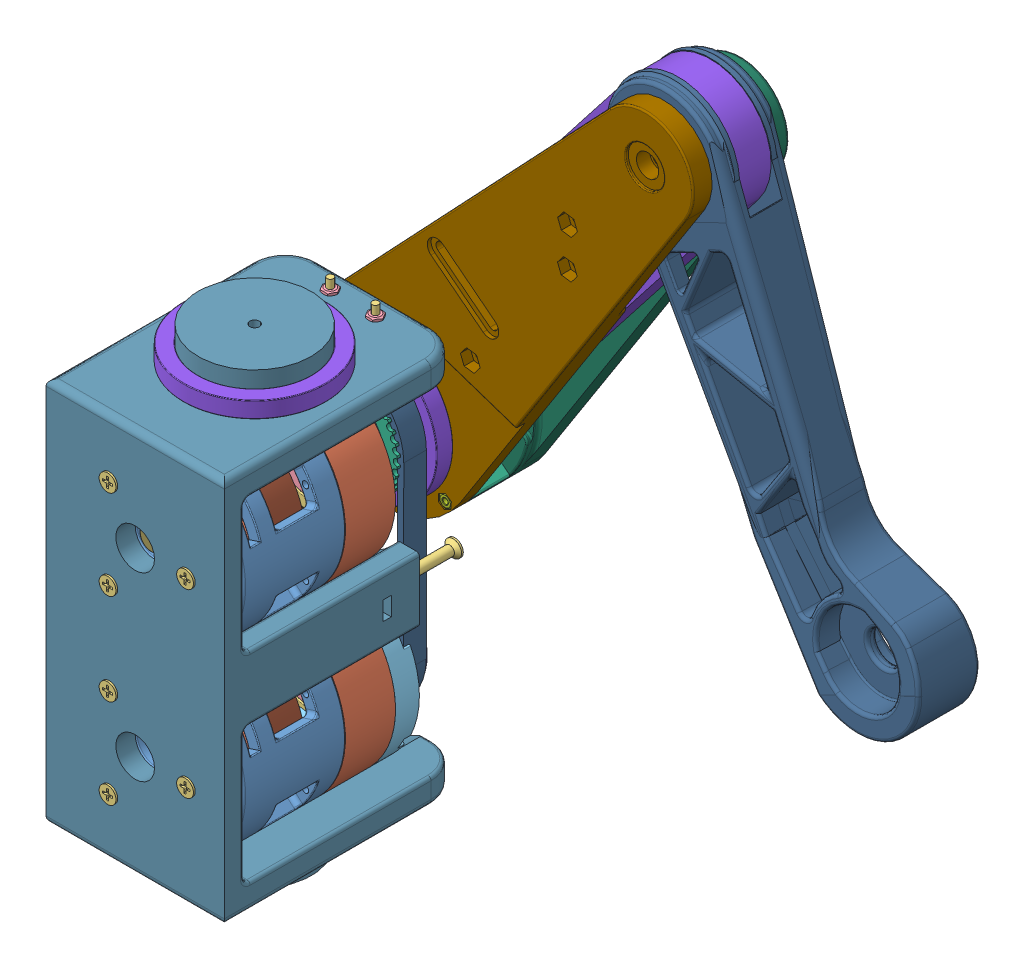
SolidWorks assembly 关节5_0版本, configuration 默认. Lengths in mm.
Overall size (206.88 234.04 105.8).
72 component instances, 34 part files, 145 mates.
Components (placement in the parent):
- 电机座-1: 电机座 [默认] at (-8.5436 5.9652 39.45) size (55.2 55.2 31.5)
- 减速器壳体-1: 减速器壳体 [默认] at (-8.5436 5.9652 32.95) x (-0.630606 -0.776103 0) z (0 0 -1) size (55.2 55.2 15.5)
- 减速器上盖-1: 减速器上盖 [默认] at (-8.5436 5.9652 18.45) x (0.969233 -0.246145 0) z (0 0 1) size (55.2 55.2 7.4) (hidden)
- 30-37-4轴承6-1: 30-37-4轴承6 [默认] at (-8.5436 5.9652 17.95) x (0.205581 0.97864 0) z (0 0 1) size (37 37 4)
- 输出轴-1: 输出轴 [默认] at (-8.5436 5.9652 21.55) x (0.166349 0.986067 0) z (0 0 -1) size (35 35 10)
- 电机座-2: 电机座 [默认] at (-8.5436 -50.0348 39.45) size (55.2 55.2 31.5)
- 减速器壳体-2: 减速器壳体 [默认] at (-8.5436 -50.0348 32.95) x (-0.630606 -0.776103 0) z (0 0 -1) size (55.2 55.2 15.5)
- 减速器上盖-2: 减速器上盖 [默认] at (-8.5436 -50.0348 18.45) x (1 0.000767 0) z (0 0 1) size (55.2 55.2 7.4)
- 输出轴-2: 输出轴 [默认] at (-8.5436 -50.0348 21.55) x (-0.988058 0.154081 0) z (0 0 -1) size (35 35 10)
- 30-37-4轴承6-2: 30-37-4轴承6 [默认] at (-8.5436 -50.0348 17.95) size (37 37 4)
- 光杆同步轮10-1: 光杆同步轮10 [GearTrax] at (-8.5436 5.9652 10.55) x (0.788067 -0.615589 0) z (0 0 1) size (35.45 35.52 14.5)
- 17-23-4轴承-1: 17-23-4轴承 [默认] at (-8.5436 5.9652 8.55) x (-0.69858 -0.715532 0) z (0 0 1) size (23 23 4)
- 35-44-5轴承-1: 35-44-5轴承 [默认] at (-8.5436 5.9652 5.55) x (-0.386204 0.922413 0) z (0 0 -1) size (44 44 5)
- 大足-1: 大足 [默认] at (-8.5436 5.9652 -2.7) x (-0.788067 0.615589 0) z (0 0 1) size (55.2 177.6 19.75)
- 零件2-1: 零件2 [默认] at origin
- 小足-1: 小足 [GearTrax] at (74.5609 112.3542 -13.1) x (0.917786 0.397075 0) z (0 0 1) size (50.75 159.33 20.11)
- 零件5-1: 零件5 [默认] at (-8.5436 5.9652 8.55) x (0 -1 0) z (0 0 1)
- 保持架-1: 保持架 [默认] at (-8.5436 5.9652 0.55) x (0 -1 0) z (-1 0 0) size (112 17 56) (hidden)
- 光杆同步轮-1: 光杆同步轮 [GearTrax] at (-8.5436 5.9652 -12.25) x (0.986067 -0.166349 0) z (0 0 1) size (35.45 35.52 10)
- 传动轴-1: 传动轴 [默认] at (-8.5436 5.9652 16.55) x (-0.986067 0.166349 0) z (0 0 -1) size (20 20 39)
- 键-1: 键 [默认] at (-7.1297 14.3467 -6.9375) x (0.986067 -0.166349 0) z (0.166349 0.986067 0) size (4.2 10.5 4.5)
- 17-23-4轴承-2: 17-23-4轴承 [默认] at (-8.5436 5.9652 -18.45) x (0.398989 0.916956 0) z (0 0 -1) size (23 23 4)
- 支撑架-1: 支撑架 [默认] at (-8.5436 -22.0348 70.95) x (0 -1 0) z (-1 0 0) size (139.2 74 55.2)
- 17-23-4轴承-3: 17-23-4轴承 [默认] at (-8.5436 5.9652 -5.45) x (0.931595 -0.363497 0) z (0 0 1) size (23 23 4)
- 大足2-1: 大足2 [默认] at (-8.5436 5.9652 -17.45) x (0.788067 -0.615589 0) z (0 0 -1) size (55.62 177.6 10.15)
- 同步轮-1: 同步轮 [GearTrax] at (74.5609 112.3542 -13.1) size (35.45 35.52 10)
- 111-1: 111 [GearTrax] at (-8.5436 -50.0348 5.3204) x (-1 0.000603 0) z (0 0 -1) size (36 36 12)
- 张紧轮-1: 张紧轮 [默认] at (-20.9196 -21.7585 13.55) x (0.998843 -0.048088 0) z (0.048088 0.998843 0) size (4.1 6.5 4.1)
- 端盖-1: 端盖 [默认] at (-8.5436 5.9652 -22.95) x (0.94954 -0.313647 0) z (0.313647 0.94954 0) size (22 3 22)
- cross countersunk head screw_as-2: cross countersunk head screw_as [AS-NZS 1023 CC- M2 x 12-N] at (-16.5463 -4.2797 -5.8) x (0 0 1) z (0.001298 -0.999999 0) size (12 3.8 3.8)
- cross countersunk head screw_as-3: cross countersunk head screw_as [AS-NZS 1023 CC- M2 x 16-N] at (-18.7885 13.9678 -6) x (0 0 1) z (-0.923728 -0.383049 0) size (16 3.8 3.8)
- cross countersunk head screw_as-4: cross countersunk head screw_as [AS-NZS 1023 CC- M2 x 16-N] at (-0.541 16.21 -6) x (0 0 1) z (-0.923728 -0.383049 0) size (16 3.8 3.8)
- cross recessed countersunk head screws gb1-2: cross recessed countersunk head screws gb1 [GB_CROSS_SCREWS_TYPE4 M2X14-12.8  H type-N] at (-1.5436 -71.0848 9.55) x (0 -1 0) z (-0.757131 0 0.653264) size (14 3.5 3.5)
- cross recessed countersunk head screws gb1-4: cross recessed countersunk head screws gb1 [GB_CROSS_SCREWS_TYPE4 M2X14-12.8  H type-N] at (-15.5436 27.5152 9.55) x (0 1 0) z (-0.215611 0 0.976479) size (14 3.5 3.5)
- cross recessed countersunk head screws gb1-5: cross recessed countersunk head screws gb1 [GB_CROSS_SCREWS_TYPE4 M2X14-12.8  H type-N] at (-15.5436 -71.0848 9.55) x (0 -1 0) z (-0.946389 0 -0.32303) size (14 3.5 3.5)
- cross recessed countersunk head screws gb1-6: cross recessed countersunk head screws gb1 [GB_CROSS_SCREWS_TYPE4 M3X30-28.35  H type-N] at (13.0564 -21.7585 -0.45) x (0 0 1) z (-1 0 0) size (30 5.2 5.2)
- cross recessed countersunk head screws gb1-7: cross recessed countersunk head screws gb1 [GB_CROSS_SCREWS_TYPE4 M3X30-28.35  H type-N] at (-30.1436 -21.7585 -0.45) x (0 0 1) z (0 1 0) size (30 5.2 5.2) (hidden)
- cross recessed countersunk head screws gb1-8: cross recessed countersunk head screws gb1 [GB_CROSS_SCREWS_TYPE4 M2X10-8.8  H type-N] at (0.1136 -55.0401 7.1) x (0 0 1) z (-0.066077 0.997815 0) size (10 3.5 3.5)
- cross recessed countersunk head screws gb1-9: cross recessed countersunk head screws gb1 [GB_CROSS_SCREWS_TYPE4 M2X10-8.8  H type-N] at (-8.5376 -40.0348 7.1) x (0 0 1) z (0.070804 -0.99749 0) size (10 3.5 3.5)
- cross recessed countersunk head screws gb1-10: cross recessed countersunk head screws gb1 [GB_CROSS_SCREWS_TYPE4 M2X10-8.8  H type-N] at (-17.2069 -55.0296 7.1) x (0 0 1) z (0.420444 -0.907319 0) size (10 3.5 3.5)
- hex thin nuts-grades ab-chamfered gb-1: hex thin nuts-grades ab-chamfered gb [GB_FASTENER_NUT_STNAB M2-N] at (-15.5436 38.7652 9.55) x (1 0 0) z (0 1 0) size (4.62 4 1.2)
- hex thin nuts-grades ab-chamfered gb-2: hex thin nuts-grades ab-chamfered gb [GB_FASTENER_NUT_STNAB M2-N] at (-1.5436 38.7652 9.55) x (1 0 0) z (0 1 0) size (4.62 4 1.2)
- hex thin nuts-grades ab-chamfered gb-3: hex thin nuts-grades ab-chamfered gb [GB_FASTENER_NUT_STNAB M2-N] at (-15.5436 -82.8348 9.55) x (0.837169 0 0.546944) z (0 -1 0) size (4.62 4 1.2)
- hex thin nuts-grades ab-chamfered gb-4: hex thin nuts-grades ab-chamfered gb [GB_FASTENER_NUT_STNAB M2-N] at (-1.5436 -82.8348 9.55) x (0.837169 0 0.546944) z (0 -1 0) size (4.62 4 1.2)
- 定位环-1: 定位环 [默认] at (-8.5436 5.9652 -7.25) x (0.991883 0.127157 0) z (0.127157 -0.991883 0) size (20.4 1.65 20.4)
- cross recessed countersunk head screws gb1-11: cross recessed countersunk head screws gb1 [GB_CROSS_SCREWS_TYPE4 M3X14-12.35  H type-N] at (-16.5436 19.8216 77.5) x (0 0 -1) z (1 0 0) size (14 5.2 5.2)
- cross recessed countersunk head screws gb1-12: cross recessed countersunk head screws gb1 [GB_CROSS_SCREWS_TYPE4 M3X14-12.35  H type-N] at (-16.5436 -7.8913 77.5) x (0 0 -1) z (1 0 0) size (14 5.2 5.2)
- cross recessed countersunk head screws gb1-13: cross recessed countersunk head screws gb1 [GB_CROSS_SCREWS_TYPE4 M3X14-12.35  H type-N] at (7.4564 5.9652 77.5) x (0 0 -1) z (1 0 0) size (14 5.2 5.2)
- cross recessed countersunk head screws gb1-14: cross recessed countersunk head screws gb1 [GB_CROSS_SCREWS_TYPE4 M3X14-12.35  H type-N] at (-16.5436 -36.1784 77.5) x (0 0 -1) z (1 0 0) size (14 5.2 5.2)
- cross recessed countersunk head screws gb1-15: cross recessed countersunk head screws gb1 [GB_CROSS_SCREWS_TYPE4 M3X14-12.35  H type-N] at (7.4564 -50.0348 77.5) x (0 0 -1) z (1 0 0) size (14 5.2 5.2)
- cross recessed countersunk head screws gb1-16: cross recessed countersunk head screws gb1 [GB_CROSS_SCREWS_TYPE4 M3X14-12.35  H type-N] at (-16.5436 -63.8913 77.5) x (0 0 -1) z (1 0 0) size (14 5.2 5.2)
- 支撑半环-1: 支撑半环 [默认] at (-8.5436 5.9652 -17.45) x (-0.788117 0.615526 0) z (0.615526 0.788117 0) size (55.19 11.85 27.6)
- hex nuts, style 1-grades ab gb-1: hex nuts, style 1-grades ab gb [GB_FASTENER_NUT_SNAB1 M3-N] at (13.0564 -21.7585 27.65) x (0.971016 0.239013 0) z (0 0 1) size (6.35 5.5 2.4)
- hex nuts, style 1-grades ab gb-2: hex nuts, style 1-grades ab gb [GB_FASTENER_NUT_SNAB1 M3-N] at (-30.1436 -21.7585 27.65) size (6.35 5.5 2.4)
- 零件2^关节5_0版本-1: 零件2^关节5_0版本 [默认] at origin (virtual)
- 同步带-1: 同步带 [默认] at (-8.5436 5.9652 -18.1) x (0.615589 0.788067 0) z (0.788067 -0.615589 0) size (172.52 10 37.52)
- 定位环_17_20_1-2mm-1: 定位环_17_20_1-2mm [默认] at (-8.5436 5.9652 -18.45) x (1 0 0) z (0 -1 0) size (20 1.2 20)
- 同步带168-2: 同步带168 [默认] at (-8.5436 5.9652 5.55) x (-0.000603 -1 0) z (-1 0.000603 0) size (93.52 7 37.52)
- cross recessed countersunk head screws gb1-17: cross recessed countersunk head screws gb1 [GB_CROSS_SCREWS_TYPE4 M2X14-12.8  H type-N] at (-1.5436 27.5152 9.55) x (0 1 0) z (-0.215611 0 0.976479) size (14 3.5 3.5)
- cross recessed countersunk head screws gb1-18: cross recessed countersunk head screws gb1 [GB_CROSS_SCREWS_TYPE4 M2X16-14.8  H type-N] at (-20.9196 -21.7585 2.1) x (0 0 1) z (0.635217 0.772334 0) size (16 3.5 3.5)
- hex nuts, style 1-grades ab gb-3: hex nuts, style 1-grades ab gb [GB_FASTENER_NUT_SNAB1 M2-N] at (-20.9196 -21.7585 16.55) size (4.62 4 1.6)
- hex nuts, style 1-grades ab gb-4: hex nuts, style 1-grades ab gb [GB_FASTENER_NUT_SNAB1 M2-N] at (9.9207 -11.0371 -0.55) x (0.905621 0.424088 0) z (0 0 1) size (4.62 4 1.6)
- hex nuts, style 1-grades ab gb-5: hex nuts, style 1-grades ab gb [GB_FASTENER_NUT_SNAB1 M2-N] at (-29.5103 19.764 -0.55) x (0.89625 0.443549 0) z (0 0 1) size (4.62 4 1.6)
- hex nuts, style 1-grades ab gb-6: hex nuts, style 1-grades ab gb [GB_FASTENER_NUT_SNAB1 M2-N] at (-6.9684 -5.3378 -0.55) x (0.83225 -0.554401 0) z (0 0 1) size (4.62 4 1.6)
- cross recessed countersunk head screws gb1-20: cross recessed countersunk head screws gb1 [GB_CROSS_SCREWS_TYPE4 M2X20-18.8  H type-N] at (-23.9933 -13.8166 -28.3) x (0 0 1) z (-1 0 0) size (20 3.5 3.5) (hidden)
- cross recessed countersunk head screws gb1-21: cross recessed countersunk head screws gb1 [GB_CROSS_SCREWS_TYPE4 M2X20-18.8  H type-N] at (9.9235 -11.0341 -28.3) x (0 0 1) z (-1 0 0) size (20 3.5 3.5)
- cross recessed countersunk head screws gb1-22: cross recessed countersunk head screws gb1 [GB_CROSS_SCREWS_TYPE4 M2X20-18.8  H type-N] at (-29.5103 19.764 -28.3) x (0 0 1) z (-1 0 0) size (20 3.5 3.5) (hidden)
- cross countersunk head screw_as-5: cross countersunk head screw_as [AS-NZS 1023 CC- M2 x 12-N] at (-8.5436 5.9652 -25.7809) x (0 0 1) z (-0.983275 0.182124 0) size (12 3.8 3.8)
- 电机46-1: 电机46 [默认] at (-8.5436 5.9652 59.65) x (0.5 0.866025 0) z (-0.866025 0.5 0) size (46 26.5 46)
- 电机46-2: 电机46 [默认] at (-8.5436 -50.0348 59.65) x (0.5 0.866025 0) z (-0.866025 0.5 0) size (46 26.5 46)
- 磁铁-1: 磁铁 [默认] at (-8.5436 5.9652 68.95) x (0.972678 0.232157 0) z (0 0 1) size (7.2 7.2 3)
- 35-44-5轴承-2: 35-44-5轴承 [默认] at (-8.5436 42.5652 39.95) x (-0.622762 0 0.782412) z (0 -1 0) size (44 44 5)
Mates (geometry in assembly coordinates):
- 同心1: concentric anti-aligned: cylinder of 电机座-1 through (-8.5436 5.9652 67.45) axis (0 0 -1) radius 27.6; cylinder of 减速器壳体-1 through (-8.5436 5.9652 23.95) axis (0 0 1) radius 27.6
- 重合1: coincident anti-aligned: plane of 电机座-1 through (-8.5436 5.9652 39.45) normal (0 0 -1); plane of 减速器壳体-1 through (-8.5436 5.9652 39.45) normal (0 0 1)
- 同心2: concentric anti-aligned: cylinder of 减速器壳体-1 through (-8.5436 5.9652 23.95) axis (0 0 1) radius 27.6; cylinder of 减速器上盖-1 through (-8.5436 5.9652 23.95) axis (0 0 -1) radius 27.6
- 重合2: coincident anti-aligned: plane of 减速器壳体-1 through (-8.5436 5.9652 23.95) normal (0 0 -1); plane of 减速器上盖-1 through (-8.5436 5.9652 23.95) normal (0 0 1)
- 同心3: concentric aligned: cylinder of 减速器上盖-1 through (-8.5436 5.9652 21.95) axis (0 0 -1) radius 18.5; cylinder of 30-37-4轴承6-1 through (-8.5436 5.9652 21.95) axis (0 0 -1) radius 18.5
- 重合3: coincident anti-aligned: plane of 减速器上盖-1 through (-8.5436 5.9652 21.95) normal (0 0 -1); plane of 30-37-4轴承6-1 through (-8.5436 5.9652 21.95) normal (0 0 1)
- 同心4: concentric aligned: cylinder of 30-37-4轴承6-1 through (-8.5436 5.9652 21.95) axis (0 0 -1) radius 15; cylinder of 输出轴-1 through (-8.5436 5.9652 63.9764) axis (0 0 -1) radius 15
- 重合4: coincident anti-aligned: plane of 30-37-4轴承6-1 through (-8.5436 5.9652 17.95) normal (0 0 -1); plane of 输出轴-1 through (-8.5436 5.9652 17.95) normal (0 0 1)
- 同心5: concentric anti-aligned: cylinder of 电机座-2 through (-8.5436 -50.0348 67.45) axis (0 0 -1) radius 27.6; cylinder of 减速器壳体-2 through (-8.5436 -50.0348 23.95) axis (0 0 1) radius 27.6
- 重合5: coincident anti-aligned: plane of 电机座-2 through (-8.5436 -50.0348 39.45) normal (0 0 -1); plane of 减速器壳体-2 through (-8.5436 -50.0348 39.45) normal (0 0 1)
- 同心6: concentric anti-aligned: cylinder of 减速器壳体-2 through (-8.5436 -50.0348 23.95) axis (0 0 1) radius 27.6; cylinder of 减速器上盖-2 through (-8.5436 -50.0348 23.95) axis (0 0 -1) radius 27.6
- 重合6: coincident anti-aligned: plane of 减速器壳体-2 through (-8.5436 -50.0348 23.95) normal (0 0 -1); plane of 减速器上盖-2 through (-8.5436 -50.0348 23.95) normal (0 0 1)
- 同心7: concentric aligned: cylinder of 减速器上盖-2 through (-8.5436 -50.0348 21.95) axis (0 0 -1) radius 18.5; cylinder of 30-37-4轴承6-2 through (-8.5436 -50.0348 21.95) axis (0 0 -1) radius 18.5
- 重合7: coincident anti-aligned: plane of 减速器上盖-2 through (-8.5436 -50.0348 21.95) normal (0 0 -1); plane of 30-37-4轴承6-2 through (-8.5436 -50.0348 21.95) normal (0 0 1)
- 同心8: concentric aligned: cylinder of 输出轴-2 through (-8.5436 -50.0348 63.9764) axis (0 0 -1) radius 15; cylinder of 30-37-4轴承6-2 through (-8.5436 -50.0348 21.95) axis (0 0 -1) radius 15
- 重合8: coincident anti-aligned: plane of 输出轴-2 through (-8.5436 -50.0348 17.95) normal (0 0 1); plane of 30-37-4轴承6-2 through (-8.5436 -50.0348 17.95) normal (0 0 -1)
- 重合9: coincident aligned: plane of 电机座-1 through (-8.5436 5.9652 39.45) normal (1 0 0); plane of 电机座-2 through (-8.5436 -50.0348 39.45) normal (1 0 0)
- 重合10: coincident aligned: plane of 电机座-1 through (-8.5436 5.9652 70.95) normal (0 0 1); plane of 电机座-2 through (-8.5436 -50.0348 70.95) normal (0 0 1)
- 同心10: concentric aligned: cylinder of 减速器壳体-1 through (-8.5436 5.9652 23.95) axis (0 0 1) radius 27.6; cylinder of 光杆同步轮10-1 through (-8.5436 5.9652 5.55) axis (0 0 1) radius 11.5
- 距离1: distance = 56 mm aligned: plane of 电机座-2 through (-8.5436 -50.0348 39.45) normal (0 1 0); plane of 电机座-1 through (-8.5436 5.9652 39.45) normal (0 1 0)
- 同心11: concentric anti-aligned: cylinder of 光杆同步轮10-1 through (-8.5436 5.9652 5.55) axis (0 0 1) radius 11.5; cylinder of 17-23-4轴承-1 through (-8.5436 5.9652 12.55) axis (0 0 -1) radius 8.5
- 同心12: concentric aligned: cylinder of 减速器上盖-1 through (-8.5436 5.9652 23.95) axis (0 0 -1) radius 27.6; cylinder of 大足-1 through (-8.5436 5.9652 78.3646) axis (0 0 -1) radius 27.6
- 重合19: coincident anti-aligned: plane of 大足-1 through (74.5609 112.3542 -3.6) normal (0 0 -1); plane of 小足-1 through (74.5609 112.3542 -3.6) normal (0 0 1)
- 同心17: concentric anti-aligned: cylinder of 减速器上盖-1 through (-8.5436 5.9652 23.95) axis (0 0 -1) radius 27.6; cylinder of 光杆同步轮10-1 through (-8.5436 5.9652 5.55) axis (0 0 1) radius 11.5
- 平行2: parallel anti-aligned: cylinder of 减速器上盖-1 through (-8.5436 5.9652 23.95) axis (0 0 -1) radius 27.6; cylinder of 35-44-5轴承-1 through (-8.5436 5.9652 0.55) axis (0 0 1) radius 17.5
- 同心24: concentric anti-aligned: cylinder of 减速器上盖-1 through (-8.5436 5.9652 23.95) axis (0 0 -1) radius 27.6; cylinder of 35-44-5轴承-1 through (-8.5436 5.9652 0.55) axis (0 0 1) radius 17.5
- 同心25: concentric anti-aligned: cylinder of 35-44-5轴承-1 through (-8.5436 5.9652 0.55) axis (0 0 1) radius 22; cylinder of 保持架-1 through (-8.5436 5.9652 5.55) axis (0 0 -1) radius 22
- 重合33: coincident anti-aligned: plane of 电机座-2 through (-8.5436 -50.0348 39.45) normal (1 0 0); plane of 保持架-1 through (-8.5436 5.9652 0.55) normal (-1 0 0)
- 重合35: coincident anti-aligned: plane of 减速器上盖-1 through (-8.5436 5.9652 16.55) normal (0 0 -1); plane of 保持架-1 through (-8.5436 5.9652 16.55) normal (0 0 1)
- 同心28: concentric aligned: cylinder of 大足-1 through (74.5609 112.3542 8.4) axis (0 0 -1) radius 3.47; cylinder of 小足-1 through (74.5609 112.3542 -0.0152) axis (0 0 -1) radius 6.5
- 同心29: concentric anti-aligned: cylinder of 大足-1 through (-8.5436 5.9652 78.3646) axis (0 0 -1) radius 27.6; cylinder of 光杆同步轮-1 through (-8.5436 5.9652 -12.25) axis (0 0 1) radius 17.7614
- 同心30: concentric anti-aligned: cylinder of 17-23-4轴承-1 through (-8.5436 5.9652 12.55) axis (0 0 -1) radius 8.5; cylinder of 传动轴-1 through (-8.5436 5.9652 -18.45) axis (0 0 1) radius 8.5
- 重合40: coincident anti-aligned: plane of 传动轴-1 through (-5.4902 12.0419 -4.45) normal (0.166349 0.986067 0); plane of 键-1 through (-5.4902 12.0419 -16.9375) normal (-0.166349 -0.986067 0)
- 重合45: coincident anti-aligned: plane of 电机座-1 through (-8.5436 5.9652 70.95) normal (0 0 1); plane of 支撑架-1 through (-8.5436 -22.0348 70.95) normal (0 0 -1)
- 同心32: concentric anti-aligned: cylinder of 电机座-1 through (-8.5436 5.9652 67.45) axis (0 0 -1) radius 27.6; cylinder of 支撑架-1 through (-8.5436 5.9652 70.95) axis (0 0 1) radius 6
- 平行3: parallel aligned: plane of 保持架-1 through (-36.5436 5.9652 5.55) normal (-1 0 0); plane of 支撑架-1 through (-36.1436 -77.6348 76.95) normal (-1 0 0)
- 重合49: coincident anti-aligned: plane of 35-44-5轴承-1 through (-8.5436 5.9652 0.55) normal (0 0 -1); plane of 保持架-1 through (-8.5436 5.9652 0.55) normal (0 0 1)
- 同心341: concentric anti-aligned: cylinder of 传动轴-1 through (-8.5436 5.9652 -18.45) axis (0 0 1) radius 8.5; cylinder of 17-23-4轴承-3 through (-8.5436 5.9652 -1.45) axis (0 0 -1) radius 8.5
- 同心351: concentric aligned: cylinder of 传动轴-1 through (-8.5436 5.9652 -18.45) axis (0 0 1) radius 8.5; cylinder of 17-23-4轴承-2 through (-8.5436 5.9652 -22.45) axis (0 0 1) radius 8.5
- 在位1: in place: plane of ? through (17.9461 35.4815 -16.45) normal (0 0 -1); plane of ? through (0 0 -16.45) normal (0 0 -1); moOrthogonalPlaneRef_w of ? through (17.9461 35.4815 -16.45) normal (0 0 -1); plane of ? through (0 0 -16.45) normal (0 1 0); plane of ? through (17.9461 35.4815 -16.45) normal (0 0 -1); plane of ? through (0 0 -16.45) normal (-1 0 0); plane of 大足-1 through (15.8707 37.22 -17.45) normal (0 0 -1); unknown of 大足2-1
- 重合51: coincident aligned: plane of 大足-1; plane of 大足2-1
- 重合52: coincident aligned: moOrthogonalPlaneRef_w of 大足-1; plane of 大足2-1 through (-8.5436 5.9652 -17.45) normal (-0.615589 -0.788067 0)
- 重合53: coincident anti-aligned: moOrthogonalPlaneRef_w of 大足-1; plane of 大足2-1 through (-8.5436 5.9652 -17.45) normal (0.788067 -0.615589 0)
- 同心352: concentric anti-aligned: cylinder of 小足-1 through (74.5609 112.3542 -26.1848) axis (0 0 1) radius 6.5; cylinder of 同步轮-1 through (74.5609 112.3542 -8.1) axis (0 0 -1) radius 3
- 重合55: coincident anti-aligned: plane of 小足-1 through (74.5609 112.3542 -18.1) normal (0 0 1); plane of 同步轮-1 through (56.8369 93.3542 -18.1) normal (0 0 -1)
- 重合56: coincident anti-aligned: plane of 17-23-4轴承-2 through (-8.5436 5.9652 -18.45) normal (0 0 1); plane of 大足2-1 through (-8.5436 5.9652 -18.45) normal (0 0 -1)
- 重合57: coincident anti-aligned: plane of 光杆同步轮10-1 through (-34.2075 1.9026 5.55) normal (0 0 -1); plane of 35-44-5轴承-1 through (-8.5436 5.9652 5.55) normal (0 0 1)
- 重合60: coincident anti-aligned: plane of 17-23-4轴承-1 through (-8.5436 5.9652 12.55) normal (0 0 1); plane of 传动轴-1 through (-8.5436 5.9652 12.55) normal (0 0 -1)
- 同心353: concentric aligned: cylinder of 减速器上盖-2 through (-8.5436 -50.0348 23.95) axis (0 0 -1) radius 27.6; cylinder of 111-1 through (-8.5436 -50.0348 17.7) axis (0 0 -1) radius 18
- 重合62: coincident anti-aligned: plane of 输出轴-2 through (-8.5436 -50.0348 16.55) normal (0 0 -1); plane of 111-1 through (-8.5436 -50.0348 16.55) normal (0 0 1)
- 重合63: coincident anti-aligned: plane of 保持架-1 through (-8.5436 5.9652 13.55) normal (0 0 -1); plane of 张紧轮-1 through (-20.9196 -21.7585 13.55) normal (0 0 1)
- 同心355: concentric anti-aligned: cylinder of 传动轴-1 through (-8.5436 5.9652 -23.2784) axis (0 0 1) radius 0.85; cylinder of 端盖-1 through (-8.5436 5.9652 -22.95) axis (0 0 -1) radius 1
- 重合65: coincident anti-aligned: plane of 大足-1 through (-8.5436 5.9652 -1.45) normal (0 0 -1); plane of 17-23-4轴承-3 through (-8.5436 5.9652 -1.45) normal (0 0 1)
- 同心356: concentric aligned: cylinder of 大足-1 through (-16.5463 -4.2797 2.3377) axis (0 0 -1) radius 1; cylinder of cross countersunk head screw_as-2 through (-16.5463 -4.2797 -5.8) axis (0 0 -1) radius 1
- 距离42: distance = 0.2 mm aligned: plane of cross countersunk head screw_as-2 through (-16.5463 -4.2797 -5.8) normal (0 0 -1); plane of 大足-1 through (-8.5436 5.9652 -5.6) normal (0 0 -1)
- 同心357: concentric aligned: cylinder of 大足-1 through (-18.7885 13.9678 2.3377) axis (0 0 -1) radius 1; cylinder of cross countersunk head screw_as-3 through (-18.7885 13.9678 -6) axis (0 0 -1) radius 1
- 距离43: distance = 0.4 mm aligned: plane of cross countersunk head screw_as-3 through (-18.7885 13.9678 -6) normal (0 0 -1); plane of 大足-1 through (-8.5436 5.9652 -5.6) normal (0 0 -1)
- 同心358: concentric aligned: cylinder of 大足-1 through (-0.541 16.21 2.3377) axis (0 0 -1) radius 1; cylinder of cross countersunk head screw_as-4 through (-0.541 16.21 -6) axis (0 0 -1) radius 1
- 距离45: distance = 0.4 mm aligned: plane of cross countersunk head screw_as-4 through (-0.541 16.21 -6) normal (0 0 -1); plane of 大足-1 through (-8.5436 5.9652 -5.6) normal (0 0 -1)
- 同心360: concentric anti-aligned: cylinder of 光杆同步轮10-1 through (-0.541 16.21 0.55) axis (0 0 1) radius 1; cylinder of cross countersunk head screw_as-4 through (-0.541 16.21 -6) axis (0 0 -1) radius 1
- 重合66: coincident anti-aligned: plane of 输出轴-1 through (-11.8225 10.5748 11.55) normal (-0.986067 0.166349 0); plane of 传动轴-1 through (-13.1533 2.6863 10.55) normal (0.986067 -0.166349 0)
- 重合67: coincident anti-aligned: plane of 输出轴-1 through (-8.5436 5.9652 16.55) normal (0 0 -1); plane of 传动轴-1 through (-8.5436 5.9652 16.55) normal (0 0 1)
- 同心361: concentric aligned: cylinder of 支撑架-1 through (-1.5436 47.5652 9.55) axis (0 -1 0) radius 1; cylinder of cross recessed countersunk head screws gb1-2 through (-1.5436 -75.6007 9.55) axis (0 -1 0) radius 1
- 重合68: coincident aligned: circle of 支撑架-1; cylinder of cross recessed countersunk head screws gb1-5 through (-15.5436 -75.6007 9.55) axis (0 -1 0) radius 1
- 同心362: concentric anti-aligned: cylinder of 支撑架-1 through (-15.5436 47.5652 9.55) axis (0 -1 0) radius 1; cylinder of cross recessed countersunk head screws gb1-4 through (-15.5436 32.031 9.55) axis (0 1 0) radius 1
- 同心366: concentric anti-aligned: cylinder of 保持架-1 through (-30.1436 -21.7585 20.6512) axis (0 0 -1) radius 1.45; cylinder of cross recessed countersunk head screws gb1-7 through (-30.1436 -21.7585 4.0658) axis (0 0 1) radius 1.5
- 同心367: concentric anti-aligned: cylinder of 保持架-1 through (13.0564 -21.7585 20.6512) axis (0 0 -1) radius 1.45; cylinder of cross recessed countersunk head screws gb1-6 through (13.0564 -21.7585 4.0658) axis (0 0 1) radius 1.5
- 同心368: concentric aligned: cylinder of 111-1 through (0.1136 -55.0401 2.55) axis (0 0 1) radius 1; cylinder of cross recessed countersunk head screws gb1-8 through (0.1136 -55.0401 11.6158) axis (0 0 1) radius 1
- 同心369: concentric aligned: cylinder of 111-1 through (-17.2069 -55.0296 2.55) axis (0 0 1) radius 1; cylinder of cross recessed countersunk head screws gb1-10 through (-17.2069 -55.0296 11.6158) axis (0 0 1) radius 1
- 同心370: concentric aligned: cylinder of 111-1 through (-8.5376 -40.0348 2.55) axis (0 0 1) radius 1; cylinder of cross recessed countersunk head screws gb1-9 through (-8.5376 -40.0348 11.6158) axis (0 0 1) radius 1
- 重合71: coincident anti-aligned: plane of 111-1 through (0.1136 -55.0401 7.55) normal (0 0 -1); circle of cross recessed countersunk head screws gb1-8
- 重合72: coincident anti-aligned: plane of 111-1 through (-8.5376 -40.0348 7.55) normal (0 0 -1); circle of cross recessed countersunk head screws gb1-9
- 重合73: coincident anti-aligned: plane of 111-1 through (-17.2069 -55.0296 7.55) normal (0 0 -1); circle of cross recessed countersunk head screws gb1-10
- 重合74: coincident anti-aligned: plane of 支撑架-1 through (19.0564 -81.6348 2.95) normal (0 -1 0); plane of hex thin nuts-grades ab-chamfered gb-3 through (-15.4164 -81.6348 7.2441) normal (0 1 0)
- 重合75: coincident anti-aligned: plane of 支撑架-1 through (19.0564 -81.6348 2.95) normal (0 -1 0); plane of hex thin nuts-grades ab-chamfered gb-4 through (-1.4164 -81.6348 7.2441) normal (0 1 0)
- 重合76: coincident anti-aligned: plane of 支撑架-1 through (19.0564 37.5652 2.95) normal (0 1 0); plane of hex thin nuts-grades ab-chamfered gb-2 through (-2.6983 37.5652 11.55) normal (0 -1 0)
- 重合77: coincident anti-aligned: plane of 支撑架-1 through (19.0564 37.5652 2.95) normal (0 1 0); plane of hex thin nuts-grades ab-chamfered gb-1 through (-16.6983 37.5652 11.55) normal (0 -1 0)
- 同心371: concentric aligned: cylinder of cross recessed countersunk head screws gb1-4 through (-15.5436 32.031 9.55) axis (0 1 0) radius 1; cylinder of hex thin nuts-grades ab-chamfered gb-1 through (-15.5436 37.5652 9.55) axis (0 1 0) radius 0.7835
- 同心373: concentric aligned: cylinder of cross recessed countersunk head screws gb1-2 through (-1.5436 -75.6007 9.55) axis (0 -1 0) radius 1; circle of hex thin nuts-grades ab-chamfered gb-4
- 同心374: concentric aligned: cylinder of cross recessed countersunk head screws gb1-5 through (-15.5436 -75.6007 9.55) axis (0 -1 0) radius 1; circle of hex thin nuts-grades ab-chamfered gb-3
- 同心376: concentric anti-aligned: cylinder of 传动轴-1 through (-8.5436 5.9652 -18.45) axis (0 0 1) radius 8.5; circle of 定位环-1
- 重合79: coincident anti-aligned: plane of 大足-1 through (-8.5436 5.9652 -5.6) normal (0 0 -1); plane of 定位环-1 through (-8.5436 5.9652 -5.6) normal (0 0 1)
- 重合80: coincident anti-aligned: plane of 17-23-4轴承-2 through (-8.5436 5.9652 -22.45) normal (0 0 -1); plane of 端盖-1 through (-8.5436 5.9652 -22.45) normal (0 0 1)
- 同心377: concentric anti-aligned: cylinder of 支撑架-1 through (-16.5436 -63.8913 70.95) axis (0 0 1) radius 1.5; cylinder of cross recessed countersunk head screws gb1-16 through (-16.5436 -63.8913 72.9842) axis (0 0 -1) radius 1.5
- 重合81: coincident anti-aligned: circle of 支撑架-1; cylinder of cross recessed countersunk head screws gb1-15 through (7.4564 -50.0348 72.9842) axis (0 0 -1) radius 1.5
- 同心378: concentric anti-aligned: cylinder of 支撑架-1 through (-16.5436 -36.1784 70.95) axis (0 0 1) radius 1.5; cylinder of cross recessed countersunk head screws gb1-14 through (-16.5436 -36.1784 72.9842) axis (0 0 -1) radius 1.5
- 重合82: coincident anti-aligned: circle of 支撑架-1; cylinder of cross recessed countersunk head screws gb1-13 through (7.4564 5.9652 72.9842) axis (0 0 -1) radius 1.5
- 重合83: coincident anti-aligned: circle of 支撑架-1; cylinder of cross recessed countersunk head screws gb1-12 through (-16.5436 -7.8913 72.9842) axis (0 0 -1) radius 1.5
- 重合84: coincident anti-aligned: circle of 支撑架-1; cylinder of cross recessed countersunk head screws gb1-11 through (-16.5436 19.8216 72.9842) axis (0 0 -1) radius 1.5
- 重合85: coincident anti-aligned: plane of 支撑架-1 through (-8.5436 -22.0348 76.95) normal (0 0 1); circle of cross recessed countersunk head screws gb1-11
- 重合86: coincident anti-aligned: plane of 支撑架-1 through (-8.5436 -22.0348 76.95) normal (0 0 1); circle of cross recessed countersunk head screws gb1-13
- 重合87: coincident anti-aligned: plane of 支撑架-1 through (-8.5436 -22.0348 76.95) normal (0 0 1); circle of cross recessed countersunk head screws gb1-12
- 重合88: coincident anti-aligned: plane of 支撑架-1 through (-8.5436 -22.0348 76.95) normal (0 0 1); circle of cross recessed countersunk head screws gb1-16
- 重合89: coincident anti-aligned: plane of 支撑架-1 through (-8.5436 -22.0348 76.95) normal (0 0 1); circle of cross recessed countersunk head screws gb1-15
- 重合90: coincident anti-aligned: plane of 支撑架-1 through (-8.5436 -22.0348 76.95) normal (0 0 1); circle of cross recessed countersunk head screws gb1-14
- 同心379: concentric anti-aligned: cylinder of 大足2-1 through (-8.5436 5.9652 -27.6) axis (0 0 1) radius 27.6; cylinder of 支撑半环-1 through (-8.5436 5.9652 -5.6) axis (0 0 -1) radius 27.6
- 重合91: coincident anti-aligned: plane of 大足-1 through (-8.5436 5.9652 -5.6) normal (0 0 -1); plane of 支撑半环-1 through (-8.5436 5.9652 -5.6) normal (0 0 1)
- 同心380: concentric anti-aligned: cylinder of 大足-1 through (-29.5103 19.764 2.3377) axis (0 0 -1) radius 0.81; cylinder of 支撑半环-1 through (-29.5103 19.764 -17.45) axis (0 0 1) radius 1
- 同心381: concentric anti-aligned: cylinder of 大足2-1 through (74.5609 112.3542 -27.6) axis (0 0 1) radius 15; cylinder of 同步带-1 through (74.5609 112.3542 -8.1) axis (0 0 -1) radius 16.76
- 同心382: concentric anti-aligned: cylinder of 大足2-1 through (-8.5436 5.9652 -27.6) axis (0 0 1) radius 27.6; cylinder of 同步带-1 through (-8.5436 5.9652 -8.1) axis (0 0 -1) radius 18.76
- 重合96: coincident anti-aligned: plane of 小足-1 through (74.5609 112.3542 -18.1) normal (0 0 1); plane of 同步带-1 through (-8.5436 5.9652 -18.1) normal (0 0 -1)
- 同心383: concentric anti-aligned: cylinder of 大足2-1 through (-8.5436 5.9652 -27.6) axis (0 0 1) radius 27.6; cylinder of 定位环_17_20_1-2mm-1 through (-8.5436 5.9652 -17.25) axis (0 0 -1) radius 8.6
- 重合97: coincident anti-aligned: plane of 17-23-4轴承-2 through (-8.5436 5.9652 -18.45) normal (0 0 1); plane of 定位环_17_20_1-2mm-1 through (-8.5436 5.9652 -18.45) normal (0 0 -1)
- 重合98: coincident anti-aligned: plane of 光杆同步轮-1 through (-29.1813 -9.8217 -17.25) normal (0 0 -1); plane of 定位环_17_20_1-2mm-1 through (-8.5436 5.9652 -17.25) normal (0 0 1)
- 重合99: coincident aligned: plane of 保持架-1 through (-8.5436 5.9652 -0.45) normal (0 0 -1); plane of cross recessed countersunk head screws gb1-7 through (-27.5436 -21.7585 -0.45) normal (0 0 -1)
- 重合100: coincident aligned: plane of 保持架-1 through (-8.5436 5.9652 -0.45) normal (0 0 -1); plane of cross recessed countersunk head screws gb1-6 through (13.0564 -19.1585 -0.45) normal (0 0 -1)
- 同心389: concentric aligned: cylinder of 光杆同步轮10-1 through (-8.5436 5.9652 8.55) axis (0 0 -1) radius 9.5; cylinder of 同步带168-2 through (-8.5436 5.9652 12.55) axis (0 0 -1) radius 16.76
- 重合102: coincident anti-aligned: plane of 光杆同步轮10-1 through (-8.5436 5.9652 5.55) normal (0 0 1); plane of 同步带168-2 through (-8.5436 5.9652 5.55) normal (0 0 -1)
- 平行7: parallel aligned: plane of 111-1 through (-8.5436 -50.0348 5.3204) normal (-1 0.000603 0); plane of 同步带168-2 through (-27.3036 5.9765 12.55) normal (-1 0.000603 0)
- 重合103: coincident anti-aligned: plane of 保持架-1 through (-8.5436 27.9652 4.55) normal (0 -1 0); circle of cross recessed countersunk head screws gb1-4
- 重合105: coincident anti-aligned: plane of 保持架-1 through (-8.5436 -71.5348 5.55) normal (0 1 0); circle of cross recessed countersunk head screws gb1-2
- 重合106: coincident anti-aligned: plane of 保持架-1 through (-8.5436 -71.5348 5.55) normal (0 1 0); circle of cross recessed countersunk head screws gb1-5
- 同心390: concentric anti-aligned: cylinder of 保持架-1 through (-1.5436 33.9652 9.55) axis (0 -1 0) radius 1; cylinder of cross recessed countersunk head screws gb1-17 through (-1.5436 32.031 9.55) axis (0 1 0) radius 1
- 重合108: coincident aligned: plane of cross recessed countersunk head screws gb1-4 through (-16.5201 41.5152 9.3344) normal (0 1 0); plane of cross recessed countersunk head screws gb1-17 through (-2.5201 41.5152 9.3344) normal (0 1 0)
- 同心394: concentric aligned: cylinder of cross recessed countersunk head screws gb1-6 through (13.0564 -21.7585 4.0658) axis (0 0 1) radius 1.5; cylinder of hex nuts, style 1-grades ab gb-1 through (13.0564 -21.7585 25.25) axis (0 0 1) radius 1.2295
- 重合109: coincident anti-aligned: plane of 支撑架-1 through (9.0564 -18.7372 25.25) normal (0 0 1); plane of hex nuts, style 1-grades ab gb-1 through (16.1398 -20.9996 25.25) normal (0 0 -1)
- 同心397: concentric aligned: cylinder of cross recessed countersunk head screws gb1-7 through (-30.1436 -21.7585 4.0658) axis (0 0 1) radius 1.5; cylinder of hex nuts, style 1-grades ab gb-2 through (-30.1436 -21.7585 25.25) axis (0 0 1) radius 1.2295
- 重合112: coincident anti-aligned: plane of 支撑架-1 through (-26.1436 -18.7372 25.25) normal (0 0 1); plane of hex nuts, style 1-grades ab gb-2 through (-26.9682 -21.7585 25.25) normal (0 0 -1)
- 重合113: coincident anti-aligned: plane of 光杆同步轮10-1 through (-8.5436 5.9652 0.55) normal (0 0 -1); plane of 大足-1 through (-8.5436 5.9652 0.55) normal (0 0 1)
- 重合122: coincident anti-aligned: plane of 保持架-1 through (-25.1436 -21.7585 2.55) normal (0 0 -1); circle of cross recessed countersunk head screws gb1-18
- 同心399: concentric aligned: cylinder of 张紧轮-1 through (-20.9196 -21.7585 6.05) axis (0 0 1) radius 1.05; cylinder of cross recessed countersunk head screws gb1-18 through (-20.9196 -21.7585 6.6158) axis (0 0 1) radius 1
- 同心400: concentric aligned: cylinder of cross recessed countersunk head screws gb1-18 through (-20.9196 -21.7585 6.6158) axis (0 0 1) radius 1; cylinder of hex nuts, style 1-grades ab gb-3 through (-20.9196 -21.7585 14.95) axis (0 0 1) radius 0.7835
- 同心401: concentric anti-aligned: cylinder of 大足-1 through (-29.5103 19.764 2.3377) axis (0 0 -1) radius 0.81; cylinder of hex nuts, style 1-grades ab gb-5 through (-29.5103 19.764 -2.15) axis (0 0 1) radius 0.7835
- 重合123: coincident anti-aligned: plane of 大足-1 through (-8.5436 5.9652 -2.15) normal (0 0 1); plane of hex nuts, style 1-grades ab gb-5 through (-27.4405 20.7883 -2.15) normal (0 0 -1)
- 平行8: parallel anti-aligned: plane of 大足-1 through (-31.3882 21.0149 -2.15) normal (0.99795 -0.064001 0); plane of hex nuts, style 1-grades ab gb-5 through (-31.4323 21.0443 -2.15) normal (-0.99795 0.064001 0)
- 重合126: coincident anti-aligned: plane of 大足-1 through (-8.5436 5.9652 -2.15) normal (0 0 1); plane of hex nuts, style 1-grades ab gb-6 through (-5.0464 -6.6182 -2.15) normal (0 0 -1)
- 重合128: coincident anti-aligned: plane of 大足-1 through (-24.1393 -16.0671 -2.15) normal (-0.443549 0.89625 0); plane of hex nuts, style 1-grades ab gb-6 through (-7.1162 -7.6425 -2.15) normal (0.443549 -0.89625 0)
- 平行11: parallel anti-aligned: cylinder of 大足-1 through (-23.9949 -13.8153 2.3377) axis (0 0 -1) radius 0.81; cylinder of hex nuts, style 1-grades ab gb-6 through (-6.9684 -5.3378 -2.15) axis (0 0 1) radius 0.7835
- 同心409: concentric anti-aligned: cylinder of 大足-1 through (9.9207 -11.0371 2.3377) axis (0 0 -1) radius 0.81; cylinder of hex nuts, style 1-grades ab gb-4 through (9.9207 -11.0371 -2.15) axis (0 0 1) radius 0.7835
- 重合129: coincident anti-aligned: plane of 大足-1 through (-8.5436 5.9652 -2.15) normal (0 0 1); plane of hex nuts, style 1-grades ab gb-4 through (12.0122 -10.0577 -2.15) normal (0 0 -1)
- 同心410: concentric anti-aligned: cylinder of 大足2-1 through (-29.5103 19.764 -17.4175) axis (0 0 -1) radius 1; cylinder of cross recessed countersunk head screws gb1-22 through (-29.5103 19.764 -23.7842) axis (0 0 1) radius 1
- 同心411: concentric anti-aligned: cylinder of 大足2-1 through (9.9235 -11.0341 -17.4175) axis (0 0 -1) radius 1; cylinder of cross recessed countersunk head screws gb1-21 through (9.9235 -11.0341 -23.7842) axis (0 0 1) radius 1
- 同心412: concentric anti-aligned: cylinder of 大足2-1 through (-23.9933 -13.8166 -17.4175) axis (0 0 -1) radius 1; cylinder of cross recessed countersunk head screws gb1-20 through (-23.9933 -13.8166 -23.7842) axis (0 0 1) radius 1
- 同心413: concentric aligned: cylinder of 端盖-1 through (-8.5436 5.9652 -22.95) axis (0 0 -1) radius 1; cylinder of cross countersunk head screw_as-5 through (-8.5436 5.9652 -25.7809) axis (0 0 -1) radius 1
- 重合130: coincident aligned: plane of 端盖-1 through (-8.5436 5.9652 -25.45) normal (0 0 -1); circle of cross countersunk head screw_as-5
- 同心414: concentric anti-aligned: cylinder of 电机座-2 through (-8.5436 -50.0348 67.45) axis (0 0 -1) radius 23.75; cylinder of 电机46-2 through (-8.5436 -50.0348 58.65) axis (0 0 1) radius 23
- 同心415: concentric anti-aligned: cylinder of 电机座-1 through (-8.5436 5.9652 67.45) axis (0 0 -1) radius 23.75; cylinder of 电机46-1 through (-8.5436 5.9652 58.65) axis (0 0 1) radius 23
- 重合131: coincident anti-aligned: plane of 电机座-1 through (-8.5436 5.9652 67.45) normal (0 0 -1); plane of 电机46-1 through (-3.3036 -11.8364 67.45) normal (0 0 1)
- 重合132: coincident anti-aligned: plane of 电机座-2 through (-8.5436 -50.0348 67.45) normal (0 0 -1); plane of 电机46-2 through (-3.3036 -67.8364 67.45) normal (0 0 1)
- 同心416: concentric anti-aligned: cylinder of 电机座-2 through (-22.4 -58.0348 39.45) axis (0 0 1) radius 1.5; cylinder of 电机46-2 through (-22.4 -58.0348 59.65) axis (0 0 -1) radius 1.25
- 同心417: concentric anti-aligned: cylinder of 电机座-1 through (-22.4 -2.0348 39.45) axis (0 0 1) radius 1.5; cylinder of 电机46-1 through (-22.4 -2.0348 59.65) axis (0 0 -1) radius 1.25
- 同心418: concentric aligned: cylinder of 电机46-1 through (-8.5436 5.9652 53.45) axis (0 0 -1) radius 2.5; cylinder of 磁铁-1 through (-8.5436 5.9652 71.95) axis (0 0 -1) radius 3.6
- 重合133: coincident anti-aligned: plane of 电机46-1 through (-6.5436 9.4293 68.95) normal (0 0 1); plane of 磁铁-1 through (-8.5436 5.9652 68.95) normal (0 0 -1)
- 重合137: coincident: plane of 支撑架-1 through (19.0564 37.5652 2.95) normal (0 1 0); plane of 35-44-5轴承-2 through (-7.4238 37.5652 38.6433) normal (0 -1 0)
- 同心419: concentric anti-aligned: cylinder of 支撑架-1 through (-8.5436 47.5652 39.95) axis (0 -1 0) radius 17.5; cylinder of 35-44-5轴承-2 through (-7.4238 37.5652 38.6433) axis (0 1 0) radius 22
